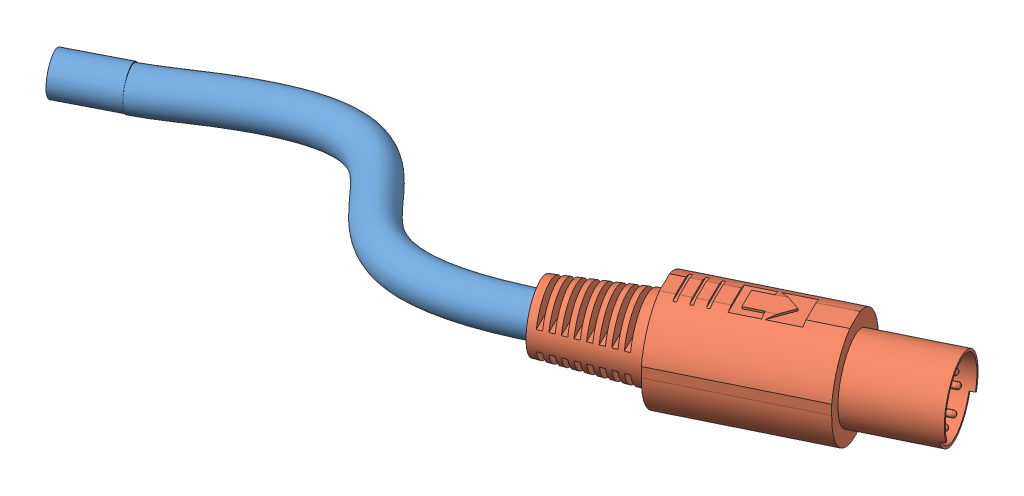
SolidWorks assembly Minidin 6, configuration Default. Lengths in mm.
Overall size (101.36 13.28 51.42).
2 component instances, 2 part files, 2 mates.
Components (placement in the parent):
- Cable-1: Cable [Default] at (-51.9892 28.2367 51.8703) x (-0.45399 0 -0.891007) z (0.891007 0 -0.45399)
- Mini din 6-1: Mini din 6 [Default] at (21.9999 31.3367 40.098) x (0.898472 0 -0.439031) z (0 1 0)
Mates (geometry in assembly coordinates):
- Concentric1: concentric aligned: circle of Cable-1; circle of Mini din 6-1
- Coincident1: coincident anti-aligned: plane of Cable-1 through (22.114 31.3367 40.0423) normal (0.898472 0 -0.439031); plane of Mini din 6-1 through (22.114 31.3367 40.0423) normal (-0.898472 0 0.439031)
